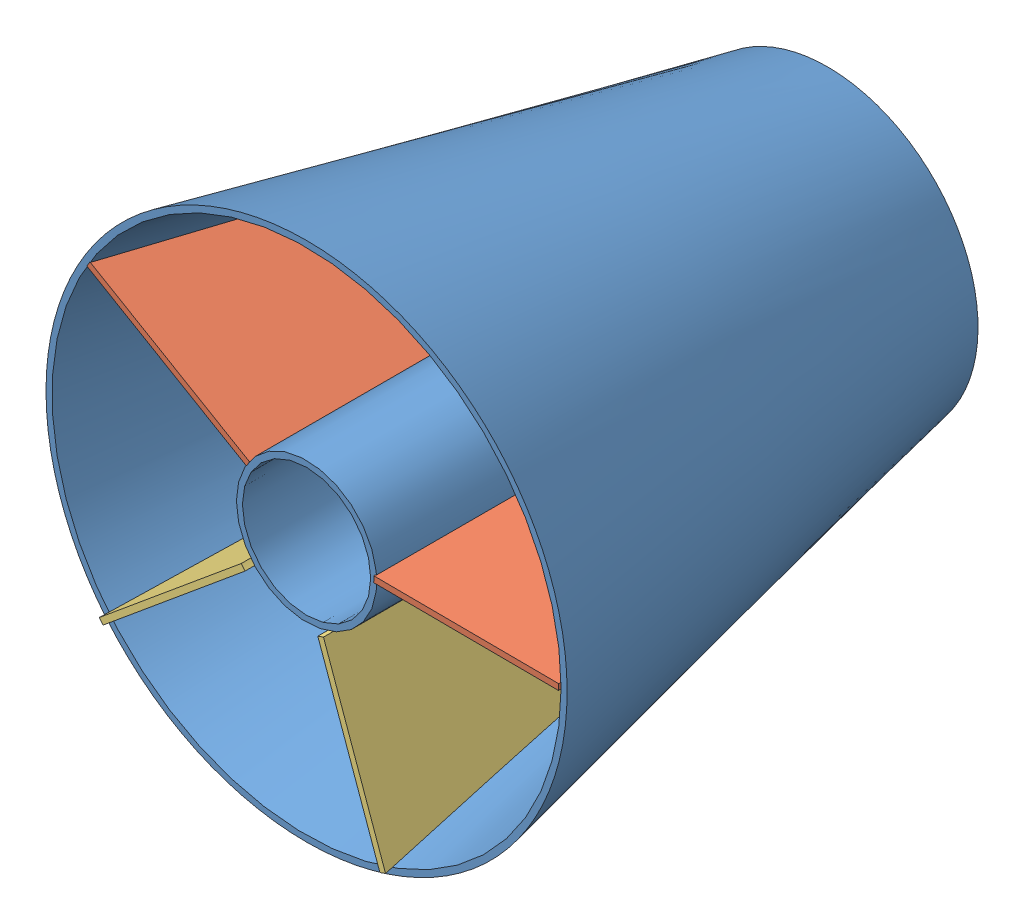
SolidWorks assembly Assem1, configuration Default. Lengths in mm.
Overall size (306.51 273.34 264.8).
4 component instances, 3 part files, 4 mates.
Components (placement in the parent):
- Part1-1: Part1 [Default] at (74.4276 180.7779 57.4746) size (265 263.73 260)
- Part2-1: Part2 [Default] at (108.8126 183.5818 61.3997) x (0.999984 -0.005705 -0.000305) z (-0.005705 -0.999984 0) size (92.26 257 3)
- Part3-1: Part3 [Default] at (74.4276 180.7779 122.2228) x (-0.005705 -0.999984 0) z (0 0 1) size (186.82 305.45 200.05)
- Part2-2: Part2 [Default] at (44.4578 198.3097 60.4746) x (-0.863159 0.504932 0) z (0.504932 0.863159 0) size (92.26 257 3)
Mates (geometry in assembly coordinates):
- Coincident7: coincident aligned: cylinder of Part1-1 through (74.4276 180.7779 317.4746) axis (0 0 -1) radius 35; circle of Part3-1
- Coincident8: coincident anti-aligned: plane of Part2-1 through (108.8103 183.1822 61.3997) normal (0.069756 -0.997564 0); plane of Part3-1 through (74.4276 180.7779 37.2228) normal (-0.069756 0.997564 0)
- Coincident9: coincident anti-aligned: plane of Part1-1 through (74.4276 180.7779 60.4746) normal (0 0 1); plane of Part2-2 through (47.7977 197.104 60.4746) normal (0 0 -1)
- Coincident10: coincident anti-aligned: plane of Part3-1; plane of Part2-2
